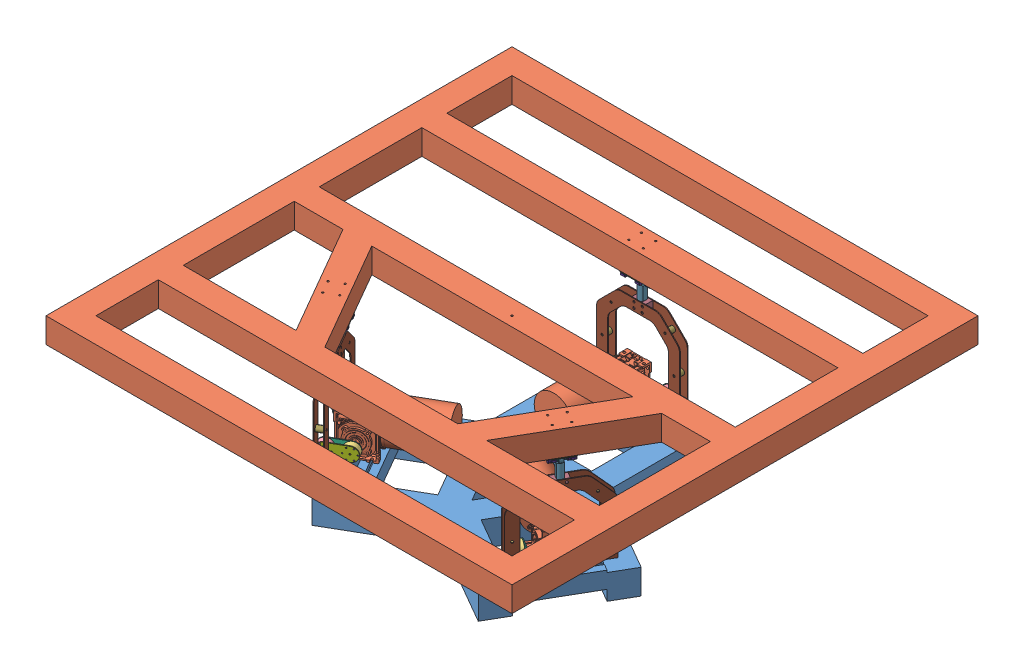
SolidWorks assembly plataforma, configuration Predeterminado. Lengths in mm.
Overall size (1680 593.5 1680).
179 component instances, 20 part files, 12 mates.
Components (placement in the parent):
- base-2: base [Predeterminado] at origin size (1029.06 97.5 891.2)
- motor con viela-1: motor con viela [Predeterminado] at (0 140 -336) size (299 406 365)
  - reductor con motor-1: reductor con motor [Predeterminado] at origin size (199 179.97 310)
  - manivela-1: manivela [Predeterminado] at (79.5 -50 -64) x (0 0 -1) z (1 0 0) size (120 50 26)
    - cople flecha-1: cople flecha [Predeterminado] at origin size (50 50 20)
    - cople rodamiento-1: cople rodamiento [Predeterminado] at (70 0 0) size (50 50 20)
    - rodameitno falso-1: rodameitno falso [Predeterminado] at (70 0 6) size (35 35 14)
    - placa manivela-2: placa manivela [Predeterminado] at (0 0 -3) size (120 50 3)
    - placa manivela 2-3: placa manivela 2 [Predeterminado] at (0 0 20) size (120 50 3)
    - tornillo falso-2: tornillo falso [Predeterminado] at (-10.5 18.1865 23) x (-0.923728 -0.383049 0) z (0 0 -1) size (4.3 4.3 26)
    - tornillo falso-3: tornillo falso [Predeterminado] at (-21 0 23) x (-0.923728 -0.383049 0) z (0 0 -1) size (4.3 4.3 26)
    - tornillo falso-4: tornillo falso [Predeterminado] at (-10.5 -18.1865 23) x (-0.923728 -0.383049 0) z (0 0 -1) size (4.3 4.3 26)
    - tornillo falso-5: tornillo falso [Predeterminado] at (10.5 -18.1865 23) x (-0.923728 -0.383049 0) z (0 0 -1) size (4.3 4.3 26)
    - tornillo falso-6: tornillo falso [Predeterminado] at (21 0 23) x (-0.923728 -0.383049 0) z (0 0 -1) size (4.3 4.3 26)
    - tornillo falso-7: tornillo falso [Predeterminado] at (10.5 18.1865 23) x (-0.923728 -0.383049 0) z (0 0 -1) size (4.3 4.3 26)
    - tornillo falso-8: tornillo falso [Predeterminado] at (59.5 18.1865 23) x (-0.923728 -0.383049 0) z (0 0 -1) size (4.3 4.3 26)
    - tornillo falso-9: tornillo falso [Predeterminado] at (49 0 23) x (-0.923728 -0.383049 0) z (0 0 -1) size (4.3 4.3 26)
    - tornillo falso-10: tornillo falso [Predeterminado] at (80.5 18.1865 23) x (-0.923728 -0.383049 0) z (0 0 -1) size (4.3 4.3 26)
    - tornillo falso-11: tornillo falso [Predeterminado] at (59.5 -18.1865 23) x (-0.923728 -0.383049 0) z (0 0 -1) size (4.3 4.3 26)
    - tornillo falso-12: tornillo falso [Predeterminado] at (80.5 -18.1865 23) x (-0.923728 -0.383049 0) z (0 0 -1) size (4.3 4.3 26)
    - tornillo falso-13: tornillo falso [Predeterminado] at (91 0 23) x (-0.923728 -0.383049 0) z (0 0 -1) size (4.3 4.3 26)
    - anillo manivela-1: anillo manivela [Predeterminado] at (70 0 0) x (0.999916 -0.012929 0) z (0 0 1) size (35 35 6)
  - manivela derecha-1: manivela derecha [Predeterminado] at (-99.5 -50 -64) x (0 0 -1) z (1 0 0) size (120 50 26)
    - cople flecha-1: cople flecha [Predeterminado] at origin size (50 50 20)
    - cople rodamiento-1: cople rodamiento [Predeterminado] at (70 0 0) size (50 50 20)
    - rodameitno falso-1: rodameitno falso [Predeterminado] at (70 0 0) size (35 35 14)
    - placa manivela 2-4: placa manivela 2 [Predeterminado] at (0 0 -3) size (120 50 3)
    - placa manivela-3: placa manivela [Predeterminado] at (0 0 20) size (120 50 3)
    - tornillo falso-2: tornillo falso [Predeterminado] at (-10.5 18.1865 23) x (-0.923728 -0.383049 0) z (0 0 -1) size (4.3 4.3 26)
    - tornillo falso-3: tornillo falso [Predeterminado] at (-21 0 23) x (-0.923728 -0.383049 0) z (0 0 -1) size (4.3 4.3 26)
    - tornillo falso-4: tornillo falso [Predeterminado] at (-10.5 -18.1865 23) x (-0.923728 -0.383049 0) z (0 0 -1) size (4.3 4.3 26)
    - tornillo falso-5: tornillo falso [Predeterminado] at (10.5 -18.1865 23) x (-0.923728 -0.383049 0) z (0 0 -1) size (4.3 4.3 26)
    - tornillo falso-6: tornillo falso [Predeterminado] at (21 0 23) x (-0.923728 -0.383049 0) z (0 0 -1) size (4.3 4.3 26)
    - tornillo falso-7: tornillo falso [Predeterminado] at (10.5 18.1865 23) x (-0.923728 -0.383049 0) z (0 0 -1) size (4.3 4.3 26)
    - tornillo falso-8: tornillo falso [Predeterminado] at (59.5 18.1865 23) x (-0.923728 -0.383049 0) z (0 0 -1) size (4.3 4.3 26)
    - tornillo falso-9: tornillo falso [Predeterminado] at (49 0 23) x (-0.923728 -0.383049 0) z (0 0 -1) size (4.3 4.3 26)
    - tornillo falso-10: tornillo falso [Predeterminado] at (80.5 18.1865 23) x (-0.923728 -0.383049 0) z (0 0 -1) size (4.3 4.3 26)
    - tornillo falso-11: tornillo falso [Predeterminado] at (59.5 -18.1865 23) x (-0.923728 -0.383049 0) z (0 0 -1) size (4.3 4.3 26)
    - tornillo falso-12: tornillo falso [Predeterminado] at (80.5 -18.1865 23) x (-0.923728 -0.383049 0) z (0 0 -1) size (4.3 4.3 26)
    - tornillo falso-13: tornillo falso [Predeterminado] at (91 0 23) x (-0.923728 -0.383049 0) z (0 0 -1) size (4.3 4.3 26)
    - anillo manivela-1: anillo manivela [Predeterminado] at (70 0 14) x (0.996967 0.077829 0) z (0 0 1) size (35 35 6)
  - pin de manivela-1: pin de manivela [Predeterminado] at (74.5 -50 -134) x (-1 0 0) z (0 0 -1) size (75 22 25)
  - pin de manivela-2: pin de manivela [Predeterminado] at (-74.5 -50 -134) size (75 22 25)
  - arco-2: arco [Predeterminado] at (0 -65 -149.5) size (299 270 3)
  - virlo-1: virlo [Predeterminado] at (129.5 35.125 -146.5) x (-0.745023 -0.667039 0) z (0 0 1) size (20 20 25)
  - virlo-2: virlo [Predeterminado] at (-129.5 35.125 -146.5) x (-0.745023 -0.667039 0) z (0 0 1) size (20 20 25)
  - virlo-3: virlo [Predeterminado] at (97.125 152.625 -146.5) x (-0.745023 -0.667039 0) z (0 0 1) size (20 20 25)
  - virlo-4: virlo [Predeterminado] at (-97.125 152.625 -146.5) x (-0.797624 -0.603155 0) z (0 0 1) size (20 20 25)
  - arco-3: arco [Predeterminado] at (0 -65 -121.5) size (299 270 3)
  - bloque-1: bloque [Predeterminado] at (0 185 -134) size (50 40 25)
  - Rotula de esfera-1: Rotula de esfera [M16] at (0 205 -134) x (0 0 1) z (-1 0 0) size (38 83 22)
    - rotula-1: rotula [M16] at origin size (38 83 22)
    - esfera-1: esfera [M16] at (0 64 0) size (30 30 21)
  - soperte superior-1: soperte superior [Predeterminado] at (0 293 -134) size (70 41 90)
    - placa superior-1: placa superior [Predeterminado] at origin size (70 3 90)
    - soporte superior-1: soporte superior [Predeterminado] at (-26 -24 0) x (0 0 1) z (-1 0 0) size (90 38 15)
    - soporte superior-2: soporte superior [Predeterminado] at (26 -24 0) x (0 0 1) z (-1 0 0) size (90 38 15)
  - pin superior-1: pin superior [Predeterminado] at (0 269 -134) size (67 16 16)
  - virlo superior-1: virlo superior [Predeterminado] at (10.5 269 -134) x (0 0.431758 -0.90199) z (1 0 0) size (22 22 8)
  - virlo superior-2: virlo superior [Predeterminado] at (-18.5 269 -134) x (0 0.14992 -0.988698) z (1 0 0) size (22 22 8)
- motor con viela-2: motor con viela [Predeterminado] at (-290.9845 140 168) x (-0.5 0 -0.866025) z (0.866025 0 -0.5) size (299 406 365)
  - reductor con motor-1: reductor con motor [Predeterminado] at origin size (199 179.97 310)
  - manivela-1: manivela [Predeterminado] at (79.5 -50 -64) x (0 0 -1) z (1 0 0) size (120 50 26)
    - cople flecha-1: cople flecha [Predeterminado] at origin size (50 50 20)
    - cople rodamiento-1: cople rodamiento [Predeterminado] at (70 0 0) size (50 50 20)
    - rodameitno falso-1: rodameitno falso [Predeterminado] at (70 0 6) size (35 35 14)
    - placa manivela-2: placa manivela [Predeterminado] at (0 0 -3) size (120 50 3)
    - placa manivela 2-3: placa manivela 2 [Predeterminado] at (0 0 20) size (120 50 3)
    - tornillo falso-2: tornillo falso [Predeterminado] at (-10.5 18.1865 23) x (-0.923728 -0.383049 0) z (0 0 -1) size (4.3 4.3 26)
    - tornillo falso-3: tornillo falso [Predeterminado] at (-21 0 23) x (-0.923728 -0.383049 0) z (0 0 -1) size (4.3 4.3 26)
    - tornillo falso-4: tornillo falso [Predeterminado] at (-10.5 -18.1865 23) x (-0.923728 -0.383049 0) z (0 0 -1) size (4.3 4.3 26)
    - tornillo falso-5: tornillo falso [Predeterminado] at (10.5 -18.1865 23) x (-0.923728 -0.383049 0) z (0 0 -1) size (4.3 4.3 26)
    - tornillo falso-6: tornillo falso [Predeterminado] at (21 0 23) x (-0.923728 -0.383049 0) z (0 0 -1) size (4.3 4.3 26)
    - tornillo falso-7: tornillo falso [Predeterminado] at (10.5 18.1865 23) x (-0.923728 -0.383049 0) z (0 0 -1) size (4.3 4.3 26)
    - tornillo falso-8: tornillo falso [Predeterminado] at (59.5 18.1865 23) x (-0.923728 -0.383049 0) z (0 0 -1) size (4.3 4.3 26)
    - tornillo falso-9: tornillo falso [Predeterminado] at (49 0 23) x (-0.923728 -0.383049 0) z (0 0 -1) size (4.3 4.3 26)
    - tornillo falso-10: tornillo falso [Predeterminado] at (80.5 18.1865 23) x (-0.923728 -0.383049 0) z (0 0 -1) size (4.3 4.3 26)
    - tornillo falso-11: tornillo falso [Predeterminado] at (59.5 -18.1865 23) x (-0.923728 -0.383049 0) z (0 0 -1) size (4.3 4.3 26)
    - tornillo falso-12: tornillo falso [Predeterminado] at (80.5 -18.1865 23) x (-0.923728 -0.383049 0) z (0 0 -1) size (4.3 4.3 26)
    - tornillo falso-13: tornillo falso [Predeterminado] at (91 0 23) x (-0.923728 -0.383049 0) z (0 0 -1) size (4.3 4.3 26)
    - anillo manivela-1: anillo manivela [Predeterminado] at (70 0 0) x (0.999916 -0.012929 0) z (0 0 1) size (35 35 6)
  - manivela derecha-1: manivela derecha [Predeterminado] at (-99.5 -50 -64) x (0 0 -1) z (1 0 0) size (120 50 26)
    - cople flecha-1: cople flecha [Predeterminado] at origin size (50 50 20)
    - cople rodamiento-1: cople rodamiento [Predeterminado] at (70 0 0) size (50 50 20)
    - rodameitno falso-1: rodameitno falso [Predeterminado] at (70 0 0) size (35 35 14)
    - placa manivela 2-4: placa manivela 2 [Predeterminado] at (0 0 -3) size (120 50 3)
    - placa manivela-3: placa manivela [Predeterminado] at (0 0 20) size (120 50 3)
    - tornillo falso-2: tornillo falso [Predeterminado] at (-10.5 18.1865 23) x (-0.923728 -0.383049 0) z (0 0 -1) size (4.3 4.3 26)
    - tornillo falso-3: tornillo falso [Predeterminado] at (-21 0 23) x (-0.923728 -0.383049 0) z (0 0 -1) size (4.3 4.3 26)
    - tornillo falso-4: tornillo falso [Predeterminado] at (-10.5 -18.1865 23) x (-0.923728 -0.383049 0) z (0 0 -1) size (4.3 4.3 26)
    - tornillo falso-5: tornillo falso [Predeterminado] at (10.5 -18.1865 23) x (-0.923728 -0.383049 0) z (0 0 -1) size (4.3 4.3 26)
    - tornillo falso-6: tornillo falso [Predeterminado] at (21 0 23) x (-0.923728 -0.383049 0) z (0 0 -1) size (4.3 4.3 26)
    - tornillo falso-7: tornillo falso [Predeterminado] at (10.5 18.1865 23) x (-0.923728 -0.383049 0) z (0 0 -1) size (4.3 4.3 26)
    - tornillo falso-8: tornillo falso [Predeterminado] at (59.5 18.1865 23) x (-0.923728 -0.383049 0) z (0 0 -1) size (4.3 4.3 26)
    - tornillo falso-9: tornillo falso [Predeterminado] at (49 0 23) x (-0.923728 -0.383049 0) z (0 0 -1) size (4.3 4.3 26)
    - tornillo falso-10: tornillo falso [Predeterminado] at (80.5 18.1865 23) x (-0.923728 -0.383049 0) z (0 0 -1) size (4.3 4.3 26)
    - tornillo falso-11: tornillo falso [Predeterminado] at (59.5 -18.1865 23) x (-0.923728 -0.383049 0) z (0 0 -1) size (4.3 4.3 26)
    - tornillo falso-12: tornillo falso [Predeterminado] at (80.5 -18.1865 23) x (-0.923728 -0.383049 0) z (0 0 -1) size (4.3 4.3 26)
    - tornillo falso-13: tornillo falso [Predeterminado] at (91 0 23) x (-0.923728 -0.383049 0) z (0 0 -1) size (4.3 4.3 26)
    - anillo manivela-1: anillo manivela [Predeterminado] at (70 0 14) x (0.996967 0.077829 0) z (0 0 1) size (35 35 6)
  - pin de manivela-1: pin de manivela [Predeterminado] at (74.5 -50 -134) x (-1 0 0) z (0 0 -1) size (75 22 25)
  - pin de manivela-2: pin de manivela [Predeterminado] at (-74.5 -50 -134) size (75 22 25)
  - arco-2: arco [Predeterminado] at (0 -65 -149.5) size (299 270 3)
  - virlo-1: virlo [Predeterminado] at (129.5 35.125 -146.5) x (-0.745023 -0.667039 0) z (0 0 1) size (20 20 25)
  - virlo-2: virlo [Predeterminado] at (-129.5 35.125 -146.5) x (-0.745023 -0.667039 0) z (0 0 1) size (20 20 25)
  - virlo-3: virlo [Predeterminado] at (97.125 152.625 -146.5) x (-0.745023 -0.667039 0) z (0 0 1) size (20 20 25)
  - virlo-4: virlo [Predeterminado] at (-97.125 152.625 -146.5) x (-0.797624 -0.603155 0) z (0 0 1) size (20 20 25)
  - arco-3: arco [Predeterminado] at (0 -65 -121.5) size (299 270 3)
  - bloque-1: bloque [Predeterminado] at (0 185 -134) size (50 40 25)
  - Rotula de esfera-1: Rotula de esfera [M16] at (0 205 -134) x (0 0 1) z (-1 0 0) size (38 83 22)
    - rotula-1: rotula [M16] at origin size (38 83 22)
    - esfera-1: esfera [M16] at (0 64 0) size (30 30 21)
  - soperte superior-1: soperte superior [Predeterminado] at (0 293 -134) size (70 41 90)
    - placa superior-1: placa superior [Predeterminado] at origin size (70 3 90)
    - soporte superior-1: soporte superior [Predeterminado] at (-26 -24 0) x (0 0 1) z (-1 0 0) size (90 38 15)
    - soporte superior-2: soporte superior [Predeterminado] at (26 -24 0) x (0 0 1) z (-1 0 0) size (90 38 15)
  - pin superior-1: pin superior [Predeterminado] at (0 269 -134) size (67 16 16)
  - virlo superior-1: virlo superior [Predeterminado] at (10.5 269 -134) x (0 0.431758 -0.90199) z (1 0 0) size (22 22 8)
  - virlo superior-2: virlo superior [Predeterminado] at (-18.5 269 -134) x (0 0.14992 -0.988698) z (1 0 0) size (22 22 8)
- motor con viela-3: motor con viela [Predeterminado] at (290.9845 140 168) x (-0.5 0 0.866025) z (-0.866025 0 -0.5) size (299 406 365)
  - reductor con motor-1: reductor con motor [Predeterminado] at origin size (199 179.97 310)
  - manivela-1: manivela [Predeterminado] at (79.5 -50 -64) x (0 0 -1) z (1 0 0) size (120 50 26)
    - cople flecha-1: cople flecha [Predeterminado] at origin size (50 50 20)
    - cople rodamiento-1: cople rodamiento [Predeterminado] at (70 0 0) size (50 50 20)
    - rodameitno falso-1: rodameitno falso [Predeterminado] at (70 0 6) size (35 35 14)
    - placa manivela-2: placa manivela [Predeterminado] at (0 0 -3) size (120 50 3)
    - placa manivela 2-3: placa manivela 2 [Predeterminado] at (0 0 20) size (120 50 3)
    - tornillo falso-2: tornillo falso [Predeterminado] at (-10.5 18.1865 23) x (-0.923728 -0.383049 0) z (0 0 -1) size (4.3 4.3 26)
    - tornillo falso-3: tornillo falso [Predeterminado] at (-21 0 23) x (-0.923728 -0.383049 0) z (0 0 -1) size (4.3 4.3 26)
    - tornillo falso-4: tornillo falso [Predeterminado] at (-10.5 -18.1865 23) x (-0.923728 -0.383049 0) z (0 0 -1) size (4.3 4.3 26)
    - tornillo falso-5: tornillo falso [Predeterminado] at (10.5 -18.1865 23) x (-0.923728 -0.383049 0) z (0 0 -1) size (4.3 4.3 26)
    - tornillo falso-6: tornillo falso [Predeterminado] at (21 0 23) x (-0.923728 -0.383049 0) z (0 0 -1) size (4.3 4.3 26)
    - tornillo falso-7: tornillo falso [Predeterminado] at (10.5 18.1865 23) x (-0.923728 -0.383049 0) z (0 0 -1) size (4.3 4.3 26)
    - tornillo falso-8: tornillo falso [Predeterminado] at (59.5 18.1865 23) x (-0.923728 -0.383049 0) z (0 0 -1) size (4.3 4.3 26)
    - tornillo falso-9: tornillo falso [Predeterminado] at (49 0 23) x (-0.923728 -0.383049 0) z (0 0 -1) size (4.3 4.3 26)
    - tornillo falso-10: tornillo falso [Predeterminado] at (80.5 18.1865 23) x (-0.923728 -0.383049 0) z (0 0 -1) size (4.3 4.3 26)
    - tornillo falso-11: tornillo falso [Predeterminado] at (59.5 -18.1865 23) x (-0.923728 -0.383049 0) z (0 0 -1) size (4.3 4.3 26)
    - tornillo falso-12: tornillo falso [Predeterminado] at (80.5 -18.1865 23) x (-0.923728 -0.383049 0) z (0 0 -1) size (4.3 4.3 26)
    - tornillo falso-13: tornillo falso [Predeterminado] at (91 0 23) x (-0.923728 -0.383049 0) z (0 0 -1) size (4.3 4.3 26)
    - anillo manivela-1: anillo manivela [Predeterminado] at (70 0 0) x (0.999916 -0.012929 0) z (0 0 1) size (35 35 6)
  - manivela derecha-1: manivela derecha [Predeterminado] at (-99.5 -50 -64) x (0 0 -1) z (1 0 0) size (120 50 26)
    - cople flecha-1: cople flecha [Predeterminado] at origin size (50 50 20)
    - cople rodamiento-1: cople rodamiento [Predeterminado] at (70 0 0) size (50 50 20)
    - rodameitno falso-1: rodameitno falso [Predeterminado] at (70 0 0) size (35 35 14)
    - placa manivela 2-4: placa manivela 2 [Predeterminado] at (0 0 -3) size (120 50 3)
    - placa manivela-3: placa manivela [Predeterminado] at (0 0 20) size (120 50 3)
    - tornillo falso-2: tornillo falso [Predeterminado] at (-10.5 18.1865 23) x (-0.923728 -0.383049 0) z (0 0 -1) size (4.3 4.3 26)
    - tornillo falso-3: tornillo falso [Predeterminado] at (-21 0 23) x (-0.923728 -0.383049 0) z (0 0 -1) size (4.3 4.3 26)
    - tornillo falso-4: tornillo falso [Predeterminado] at (-10.5 -18.1865 23) x (-0.923728 -0.383049 0) z (0 0 -1) size (4.3 4.3 26)
    - tornillo falso-5: tornillo falso [Predeterminado] at (10.5 -18.1865 23) x (-0.923728 -0.383049 0) z (0 0 -1) size (4.3 4.3 26)
    - tornillo falso-6: tornillo falso [Predeterminado] at (21 0 23) x (-0.923728 -0.383049 0) z (0 0 -1) size (4.3 4.3 26)
    - tornillo falso-7: tornillo falso [Predeterminado] at (10.5 18.1865 23) x (-0.923728 -0.383049 0) z (0 0 -1) size (4.3 4.3 26)
    - tornillo falso-8: tornillo falso [Predeterminado] at (59.5 18.1865 23) x (-0.923728 -0.383049 0) z (0 0 -1) size (4.3 4.3 26)
    - tornillo falso-9: tornillo falso [Predeterminado] at (49 0 23) x (-0.923728 -0.383049 0) z (0 0 -1) size (4.3 4.3 26)
    - tornillo falso-10: tornillo falso [Predeterminado] at (80.5 18.1865 23) x (-0.923728 -0.383049 0) z (0 0 -1) size (4.3 4.3 26)
    - tornillo falso-11: tornillo falso [Predeterminado] at (59.5 -18.1865 23) x (-0.923728 -0.383049 0) z (0 0 -1) size (4.3 4.3 26)
    - tornillo falso-12: tornillo falso [Predeterminado] at (80.5 -18.1865 23) x (-0.923728 -0.383049 0) z (0 0 -1) size (4.3 4.3 26)
    - tornillo falso-13: tornillo falso [Predeterminado] at (91 0 23) x (-0.923728 -0.383049 0) z (0 0 -1) size (4.3 4.3 26)
    - anillo manivela-1: anillo manivela [Predeterminado] at (70 0 14) x (0.996967 0.077829 0) z (0 0 1) size (35 35 6)
  - pin de manivela-1: pin de manivela [Predeterminado] at (74.5 -50 -134) x (-1 0 0) z (0 0 -1) size (75 22 25)
  - pin de manivela-2: pin de manivela [Predeterminado] at (-74.5 -50 -134) size (75 22 25)
  - arco-2: arco [Predeterminado] at (0 -65 -149.5) size (299 270 3)
  - virlo-1: virlo [Predeterminado] at (129.5 35.125 -146.5) x (-0.745023 -0.667039 0) z (0 0 1) size (20 20 25)
  - virlo-2: virlo [Predeterminado] at (-129.5 35.125 -146.5) x (-0.745023 -0.667039 0) z (0 0 1) size (20 20 25)
  - virlo-3: virlo [Predeterminado] at (97.125 152.625 -146.5) x (-0.745023 -0.667039 0) z (0 0 1) size (20 20 25)
  - virlo-4: virlo [Predeterminado] at (-97.125 152.625 -146.5) x (-0.797624 -0.603155 0) z (0 0 1) size (20 20 25)
  - arco-3: arco [Predeterminado] at (0 -65 -121.5) size (299 270 3)
  - bloque-1: bloque [Predeterminado] at (0 185 -134) size (50 40 25)
  - Rotula de esfera-1: Rotula de esfera [M16] at (0 205 -134) x (0 0 1) z (-1 0 0) size (38 83 22)
    - rotula-1: rotula [M16] at origin size (38 83 22)
    - esfera-1: esfera [M16] at (0 64 0) size (30 30 21)
  - soperte superior-1: soperte superior [Predeterminado] at (0 293 -134) size (70 41 90)
    - placa superior-1: placa superior [Predeterminado] at origin size (70 3 90)
    - soporte superior-1: soporte superior [Predeterminado] at (-26 -24 0) x (0 0 1) z (-1 0 0) size (90 38 15)
    - soporte superior-2: soporte superior [Predeterminado] at (26 -24 0) x (0 0 1) z (-1 0 0) size (90 38 15)
  - pin superior-1: pin superior [Predeterminado] at (0 269 -134) size (67 16 16)
  - virlo superior-1: virlo superior [Predeterminado] at (10.5 269 -134) x (0 0.431758 -0.90199) z (1 0 0) size (22 22 8)
  - virlo superior-2: virlo superior [Predeterminado] at (-18.5 269 -134) x (0 0.14992 -0.988698) z (1 0 0) size (22 22 8)
- base superior-1: base superior [Predeterminado] at (0 526 0) x (-1 0 0) z (0 -1 0) size (1680 1680 90)
Mates (geometry in assembly coordinates):
- Coincidente1: coincident aligned: plane of motor con viela-1 through (0 140 -336) normal (1 0 0)
- Coincidente2: coincident anti-aligned: plane of base-2 through (0 30 0) normal (0 1 0); plane of motor con viela-1/reductor con motor-1 through (-42.5 30 -460) normal (0 -1 0)
- Distancia1: distance = 10 mm aligned: plane of base-2 through (0 22.5 -470) normal (0 0 -1); plane of motor con viela-1/reductor con motor-1 through (-42.5 174 -460) normal (0 0 -1)
- Coincidente5: coincident aligned: plane of motor con viela-2 through (-290.9845 140 168) normal (-0.5 0 -0.866025)
- Coincidente6: coincident anti-aligned: plane of base-2 through (0 30 0) normal (0 1 0); plane of motor con viela-2/reductor con motor-1 through (-377.1217 30 266.8061) normal (0 -1 0)
- Distancia2: distance = 10 mm aligned: plane of motor con viela-2/reductor con motor-1 through (-377.1217 174 266.8061) normal (-0.866025 0 0.5); plane of base-2 through (-407.0319 22.5 235) normal (-0.866025 0 0.5)
- Coincidente8: coincident aligned: plane of motor con viela-3 through (290.9845 140 168) normal (-0.5 0 0.866025)
- Coincidente9: coincident anti-aligned: plane of base-2 through (0 30 0) normal (0 1 0); plane of motor con viela-3/reductor con motor-1 through (419.6217 30 193.1939) normal (0 -1 0)
- Distancia3: distance = 10 mm aligned: plane of motor con viela-3/reductor con motor-1 through (419.6217 174 193.1939) normal (0.866025 0 0.5); plane of base-2 through (407.0319 22.5 235) normal (0.866025 0 0.5)
- Coincidente10: coincident anti-aligned: plane of base superior-1 through (0 526 0) normal (-1 0 0)
- Coincidente11: coincident anti-aligned: plane of base superior-1 through (0 526 0) normal (0 0 -1)
- Coincidente12: coincident anti-aligned: plane of motor con viela-1/soperte superior-1/placa superior-1 through (0 436 -470) normal (0 1 0); plane of base superior-1 through (0 436 0) normal (0 -1 0)
